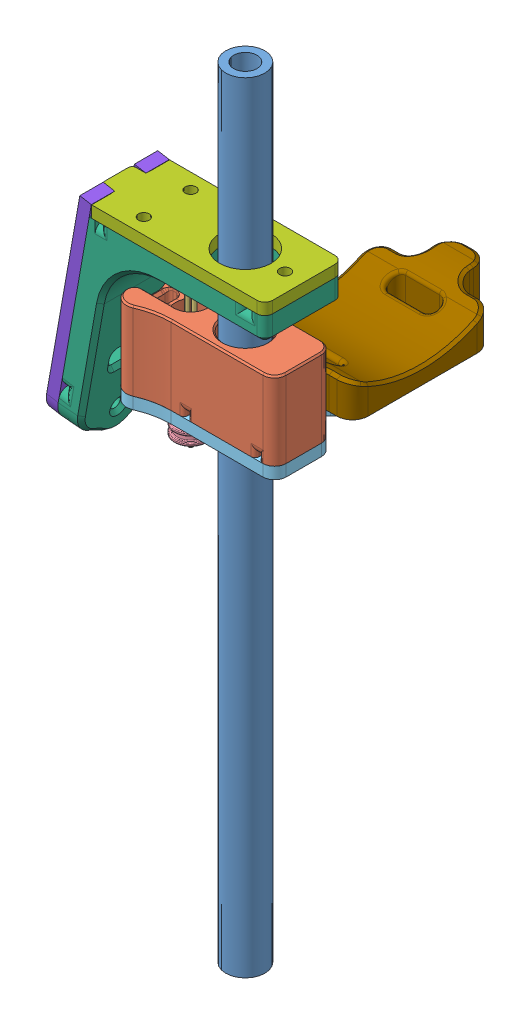
SolidWorks assembly FingerAssembly, configuration Default. Lengths in mm.
Overall size (28.67 100 33.92).
11 component instances, 9 part files, 2 mates.
Components (placement in the parent):
- CarbonFiberTube-Od5mm-Id3mm^FingerAssembly-1: CarbonFiberTube-Od5mm-Id3mm^FingerAssembly [Default] at origin size (5 100 5) (virtual)
- BrakeAssembly-1: BrakeAssembly [Default] at (0 10.2633 0) size (28.67 28.68 33.92)
  - Part2^BrakeAssembly-1: Part2^BrakeAssembly [Default] x (1 0 0) z (0 1 0) size (19.85 9.5 10) (virtual)
  - Yamnis Motor-1: Yamnis Motor [Default] at (-7 6 0) x (-0.837169 0 -0.546944) z (-0.546944 0 0.837169) size (4 22.41 4)
  - Part3^BrakeAssembly-1: Part3^BrakeAssembly [Default] at (-7 -3.3 0) x (-0.837169 0 -0.546944) z (0 -1 0) size (4.15 4.15 1.5) (virtual)
  - Part5^BrakeAssembly-1: Part5^BrakeAssembly [Default] x (-1 0 0) z (0 -1 0) size (19.75 33.5 1.5) (virtual)
  - Assem1^BrakeAssembly-1: Assem1^BrakeAssembly [Default] at origin size (28.67 28.68 10.34) (virtual)
    - Copy of Part4^Assem1_BrakeAssembly-1: Copy of Part4^Assem1_BrakeAssembly [Default] at origin size (27.27 26.91 10.34) (virtual)
    - Part1^Assem1_BrakeAssembly-1: Part1^Assem1_BrakeAssembly [Default] at (0 17.5 0) x (1 0 0) z (0 1 0) size (24.02 10 1.5) (virtual)
    - Part2^Assem1_BrakeAssembly-1: Part2^Assem1_BrakeAssembly [Default] at (-17.5571 3.0958 0) x (0 0 1) z (-0.984808 0.173648 0) size (10.02 28.42 1.52) (virtual)
  - Part4^BrakeAssembly-2: Part4^BrakeAssembly [Default] x (1 0 0) z (0 1 0) size (15 25 5) (virtual)
Mates (geometry in assembly coordinates):
- Concentric1: concentric aligned: cylinder of CarbonFiberTube-Od5mm-Id3mm^FingerAssembly-1 through (0 50 0) axis (0 -1 0) radius 2.5; cylinder of BrakeAssembly-1/Part2^BrakeAssembly-1 through (0 20.2633 0) axis (0 -1 0) radius 2.75
- Coincident1: coincident anti-aligned: plane of BrakeAssembly-1/Part2^BrakeAssembly-1 through (0 10.2633 0) normal (0 0 -1)
